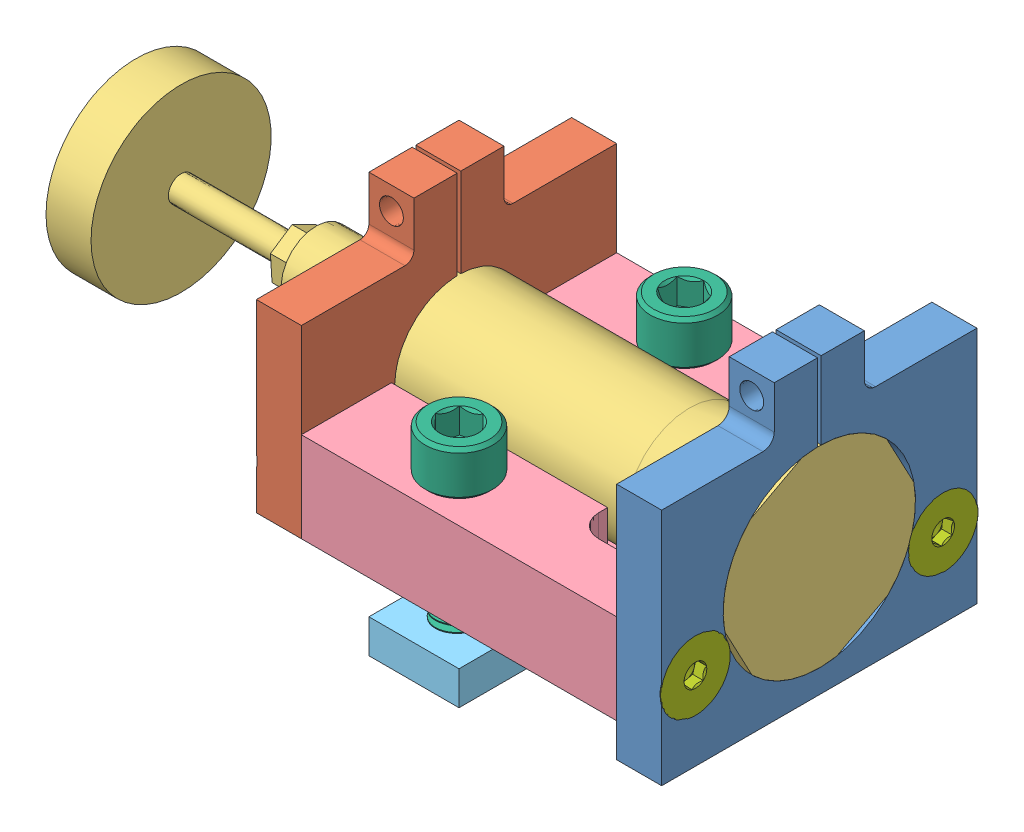
SolidWorks assembly Toolpost_Grinder_Flat_Asm, configuration Default. Lengths in mm.
Overall size (199.01 92.08 94.55).
9 component instances, 7 part files, 21 mates.
Components (placement in the parent):
- Large_Hole_Plate-1: Large_Hole_Plate [Default] at (-79.3244 31.75 -44.45) x (0 1 0) z (1 0 0) size (82.55 88.9 19.05)
- Small_Hole_Plate-1: Small_Hole_Plate [Default] at (-168.2244 33.655 -44.45) x (0 1 0) z (-1 0 0) size (67.31 88.9 19.05)
- Grinder-1: Grinder [Default] at (-183.0834 24.13 -44.45) x (0 0.470099 -0.882613) z (0 0.882613 0.470099) size (51.69 192.66 51.69)
- Horozontal_Flat_Plate-1: Horozontal_Flat_Plate [Default] at (-123.7744 0 -44.45) x (1 0 0) z (0 1 0) size (88.9 88.9 31.75)
- Cross_Slide_Clamp-1: Cross_Slide_Clamp [Default] at (-136.4744 -14.2875 -44.45) size (25.4 9.53 88.9)
- 0.5in_1.5in_Long_Allen_Cap_Screw-91251A716-1: 0.5in_1.5in_Long_Allen_Cap_Screw-91251A716 [91251A716] at (-136.4744 -12.7 -76.2) x (1 0 0) z (0 -1 0) size (19.05 19.05 53.06)
- 0.5in_1.5in_Long_Allen_Cap_Screw-91251A716-2: 0.5in_1.5in_Long_Allen_Cap_Screw-91251A716 [91251A716] at (-136.4744 -12.7 -12.7) x (-0.240592 0 -0.970626) z (0 -1 0) size (19.05 19.05 53.06)
- 0.375in_1.0in_Countersunk_Allen_Screw-1: 0.375in_1.0in_Countersunk_Allen_Screw [91253A624] at (-72.568 12.7 -9.525) x (0 -0.974425 -0.224712) z (1 0 0) size (19.72 19.72 25.73)
- 0.375in_1.0in_Countersunk_Allen_Screw-2: 0.375in_1.0in_Countersunk_Allen_Screw [91253A624] at (-72.568 12.7 -79.375) x (0 -0.924225 -0.381849) z (1 0 0) size (19.72 19.72 25.73)
Mates (geometry in assembly coordinates):
- Coincident19: coincident anti-aligned: plane of Small_Hole_Plate-1 through (-168.2244 67.31 -88.9) normal (1 0 0); plane of Horozontal_Flat_Plate-1 through (-168.2244 25.4 0) normal (-1 0 0)
- Coincident23: coincident anti-aligned: axis of Horozontal_Flat_Plate-1 through (-150.4444 12.7 -12.7) axis (-1 0 0); axis of Small_Hole_Plate-1 through (-180.9244 12.7 -12.7) axis (1 0 0)
- Coincident24: coincident anti-aligned: axis of Horozontal_Flat_Plate-1 through (-150.4444 12.7 -76.2) axis (-1 0 0); axis of Small_Hole_Plate-1 through (-180.9244 12.7 -76.2) axis (1 0 0)
- Coincident26: coincident anti-aligned: plane of Horozontal_Flat_Plate-1 through (-79.3244 0 -88.9) normal (0 -1 0); plane of assembly
- Coincident27: coincident aligned: plane of Horozontal_Flat_Plate-1 through (-168.2244 25.4 0) normal (0 0 1); plane of assembly
- Coincident32: coincident anti-aligned: axis of Small_Hole_Plate-1 through (-168.2244 24.13 -44.45) axis (-1 0 0); axis of Grinder-1 through (-208.4834 24.13 -44.45) axis (1 0 0)
- Coincident33: coincident aligned: axis of Large_Hole_Plate-1 through (-79.3244 24.13 -44.45) axis (1 0 0); axis of Grinder-1 through (-79.5784 24.13 -44.45) axis (1 0 0)
- Coincident35: coincident anti-aligned: plane of Large_Hole_Plate-1 through (-79.3244 73.025 0) normal (-1 0 0); plane of Horozontal_Flat_Plate-1 through (-79.3244 25.4 0) normal (1 0 0)
- Coincident36: coincident aligned: plane of Large_Hole_Plate-1 through (-66.6244 73.025 0) normal (1 0 0); plane of Grinder-1 through (-66.6244 11.3835 -20.5184) normal (1 0 0)
- Distance1: distance = 9.525 mm anti-aligned: plane of Horozontal_Flat_Plate-1 through (-79.3244 0 -88.9) normal (0 -1 0); plane of Cross_Slide_Clamp-1 through (-149.1744 -9.525 0) normal (0 1 0)
- Coincident38: coincident aligned: axis of Horozontal_Flat_Plate-1 through (-136.4744 0 -12.7) axis (0 1 0); axis of Cross_Slide_Clamp-1 through (-136.4744 -19.05 -12.7) axis (0 1 0)
- Coincident39: coincident aligned: axis of Horozontal_Flat_Plate-1 through (-136.4744 0 -76.2) axis (0 1 0); axis of Cross_Slide_Clamp-1 through (-136.4744 -19.05 -76.2) axis (0 1 0)
- Coincident40: coincident anti-aligned: axis of Horozontal_Flat_Plate-1 through (-136.4744 0 -76.2) axis (0 1 0); axis of 0.5in_1.5in_Long_Allen_Cap_Screw-91251A716-1 through (-136.4744 37.1475 -76.2) axis (0 -1 0)
- Coincident41: coincident anti-aligned: plane of Horozontal_Flat_Plate-1 through (-79.3244 25.4 -88.9) normal (0 1 0); plane of 0.5in_1.5in_Long_Allen_Cap_Screw-91251A716-1 through (-136.4744 25.4 -76.2) normal (0 -1 0)
- Coincident42: coincident anti-aligned: axis of Horozontal_Flat_Plate-1 through (-136.4744 0 -12.7) axis (0 1 0); axis of 0.5in_1.5in_Long_Allen_Cap_Screw-91251A716-2 through (-136.4744 37.1475 -12.7) axis (0 -1 0)
- Coincident43: coincident anti-aligned: plane of Horozontal_Flat_Plate-1 through (-79.3244 25.4 -88.9) normal (0 1 0); plane of 0.5in_1.5in_Long_Allen_Cap_Screw-91251A716-2 through (-136.4744 25.4 -12.7) normal (0 -1 0)
- Coincident50: coincident: axis of Large_Hole_Plate-1 through (-66.6244 12.7 -79.375) axis (-1 0 0); axis of Horozontal_Flat_Plate-1 through (-97.1044 12.7 -79.375) axis (1 0 0)
- Coincident51: coincident aligned: plane of 0.375in_1.0in_Countersunk_Allen_Screw-2 through (-66.6244 12.7 -79.375) normal (1 0 0); plane of Large_Hole_Plate-1 through (-66.6244 73.025 0) normal (1 0 0)
- Coincident54: coincident: axis of Large_Hole_Plate-1 through (-66.6244 12.7 -79.375) axis (-1 0 0); axis of 0.375in_1.0in_Countersunk_Allen_Screw-2 through (-69.8367 12.7 -79.375) axis (-1 0 0)
- Coincident55: coincident aligned: plane of 0.375in_1.0in_Countersunk_Allen_Screw-1 through (-66.6244 12.7 -9.525) normal (1 0 0); plane of Large_Hole_Plate-1 through (-66.6244 73.025 0) normal (1 0 0)
- Coincident56: coincident: axis of Large_Hole_Plate-1 through (-66.6244 12.7 -9.525) axis (-1 0 0); axis of 0.375in_1.0in_Countersunk_Allen_Screw-1 through (-69.8367 12.7 -9.525) axis (-1 0 0)
